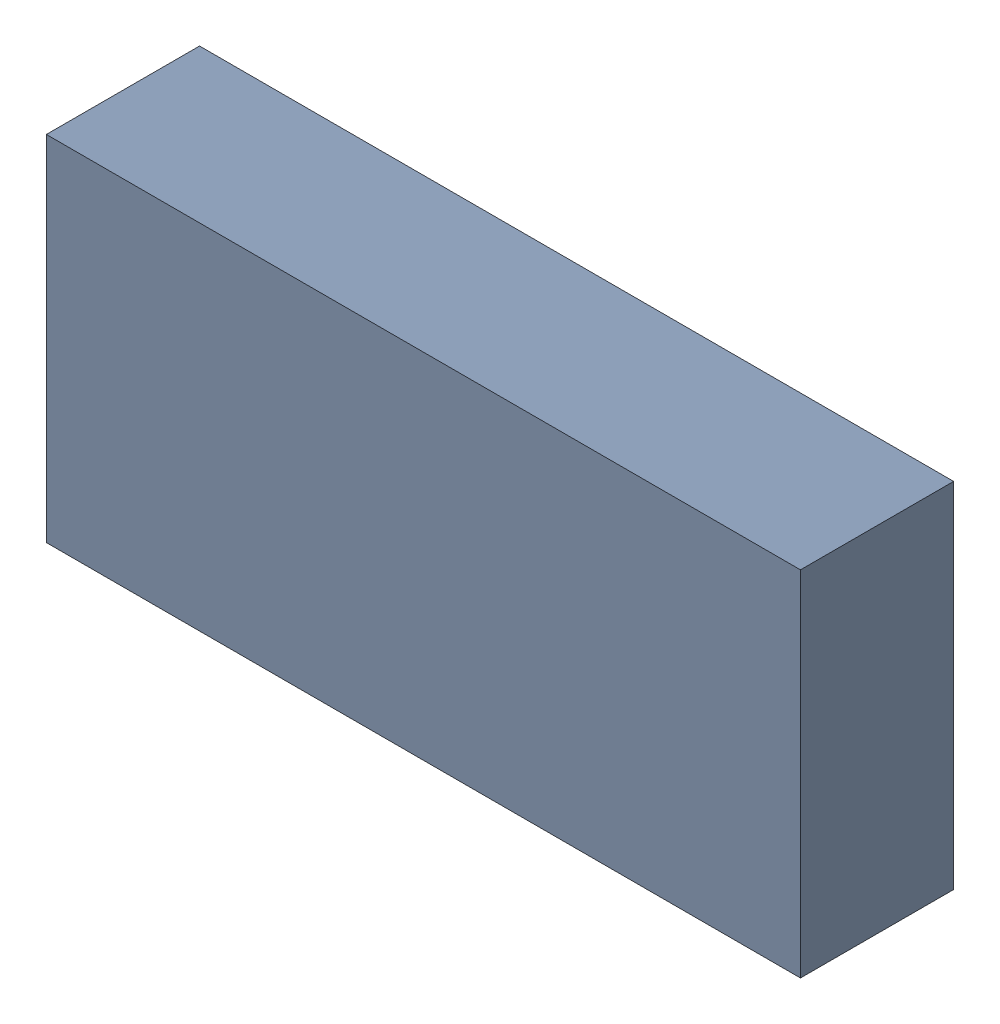
SolidWorks assembly X2, configuration Standard. Lengths in mm.
Overall size (3.2 1.5 0.65).
2 component instances, 1 part files, 0 mates.
Components (placement in the parent):
- 885545776-1: 885545776 [Standard] at (-20.27 -5.32 0) size (3.2 1.5 0.65)
  - Extruded_7-1: Extruded_7 [Standard] at origin size (3.2 1.5 0.65)
